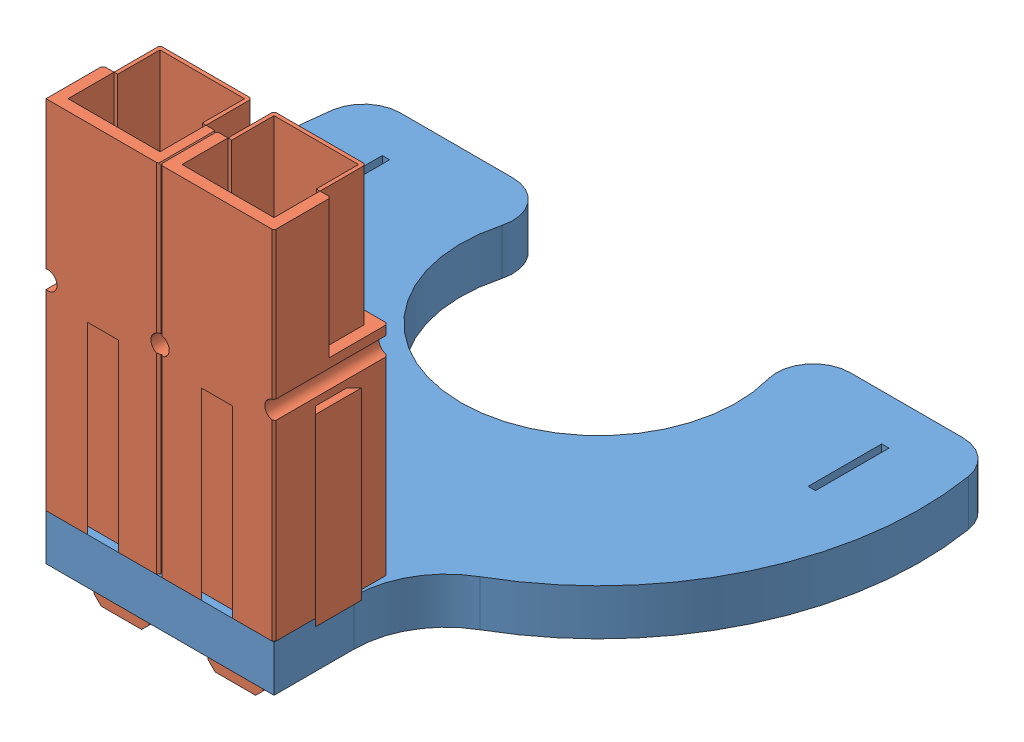
SolidWorks assembly Assem1, configuration Default. Lengths in mm.
Overall size (44.45 29.72 36.02).
2 component instances, 2 part files, 3 mates.
Components (placement in the parent):
- 775 Connector-1: 775 Connector [Default] at (7.0387 23.9643 25.0058) size (44.45 3.17 36.02)
- PowerPoles-1: PowerPoles [Default] at (3.1017 27.1393 51.3773) x (1 0 0) z (0 1 0) size (16.26 8.38 29.72)
Mates (geometry in assembly coordinates):
- Coincident1: coincident aligned: plane of 775 Connector-1 through (7.0387 27.1393 25.0058) normal (0 1 0); plane of PowerPoles-1 through (7.8007 27.1393 54.5523) normal (0 1 0)
- Coincident2: coincident aligned: plane of 775 Connector-1 through (-0.8353 27.1393 55.3143) normal (0 0 1); plane of PowerPoles-1 through (-0.8353 27.1393 55.3143) normal (0 0 1)
- Coincident3: coincident aligned: plane of 775 Connector-1 through (14.9127 27.1393 45.7893) normal (1 0 0); plane of PowerPoles-1 through (14.9127 39.4583 51.3773) normal (1 0 0)
